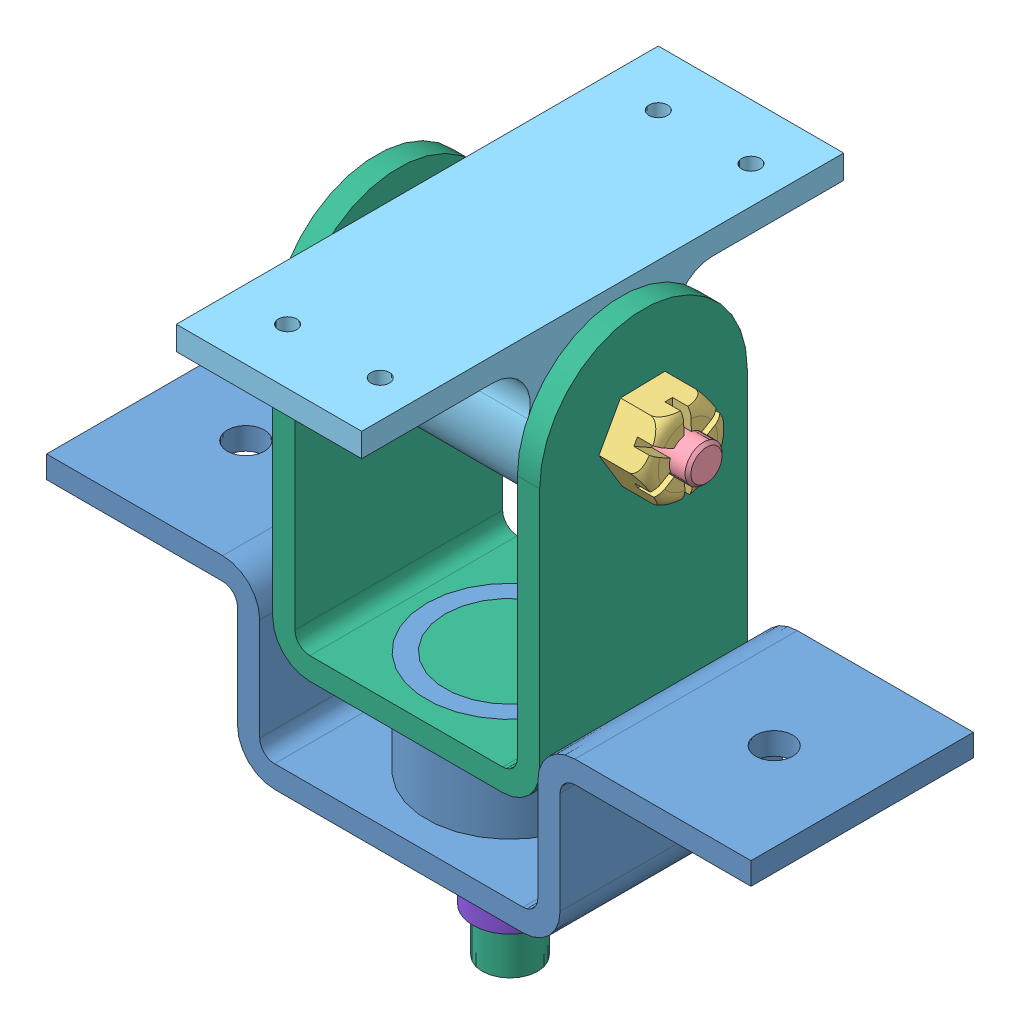
SolidWorks assembly Assem1, configuration Default. Lengths in mm.
Overall size (950 845 650).
9 component instances, 8 part files, 19 mates.
Components (placement in the parent):
- Braket-1: Braket [Default] at (414.4742 324.3872 733.1991) x (1 0 0) z (0 -1 0) size (950 300 238)
- Bushing-1: Bushing [Default] at (501.9742 844.3872 733.1991) x (0 0.51814 -0.855296) z (0 -0.855296 -0.51814) size (200 125 200)
- Castle Nut-1: Castle Nut [Default] at (624.4742 844.3872 733.1991) x (0 0.875235 -0.483697) z (0 -0.483697 -0.875235) size (123.23 61.16 107.14)
- Hexagonal Bolt-1: Hexagonal Bolt [Default] at (679.4742 844.3872 733.1991) x (0 -0.652538 0.757756) z (0 -0.757756 -0.652538) size (126.08 492.24 109.99)
- Pivot-1: Pivot [Default] at (414.4742 857.3872 733.1991) x (0 0 -1) z (1 0 0) size (650 238 250)
- U-Support-1: U-Support [Default] at (414.4742 139.3872 733.1991) size (360 845 280)
- Washer-1: Washer [Default] at (414.4742 319.3872 733.1991) size (165 10 165)
- Bushing-2: Bushing [Default] at (326.9742 844.3872 733.1991) x (0 0.946184 -0.32363) z (0 0.32363 0.946184) size (200 125 200)
- Self Locking Nut-2: Self Locking Nut [Default] at (414.4742 281.8872 733.1991) x (1 0 0) z (0 0 -1) size (188.7 115 164.72)
Mates (geometry in assembly coordinates):
- Coincident2: coincident aligned: circle of Braket-1; plane of U-Support-1 through (414.4742 494.3872 506.1991) normal (0 1 0)
- Coincident3: coincident anti-aligned: circle of Braket-1; cylinder of U-Support-1 through (414.4742 464.3872 733.1991) axis (0 -1 0) radius 37.5
- Coincident5: coincident aligned: plane of Hexagonal Bolt-1 through (234.4742 844.3872 733.1991) normal (1 0 0); circle of U-Support-1
- Concentric1: concentric aligned: cylinder of Hexagonal Bolt-1 through (234.4742 844.3872 733.1991) axis (1 0 0) radius 25; cylinder of U-Support-1 through (227.4742 844.3872 733.1991) axis (1 0 0) radius 25
- Concentric2: concentric anti-aligned: cylinder of Castle Nut-1 through (654.4742 844.3872 733.1991) axis (-1 0 0) radius 25; cylinder of Hexagonal Bolt-1 through (234.4742 844.3872 733.1991) axis (1 0 0) radius 25
- Coincident8: coincident anti-aligned: plane of Castle Nut-1 through (594.4742 844.3872 733.1991) normal (-1 0 0); plane of U-Support-1 through (594.4742 984.3872 873.1991) normal (1 0 0)
- Perpendicular1: perpendicular: plane of Castle Nut-1 through (654.4742 896.9402 704.1558) normal (0 0.999825 0.018724); plane of U-Support-1 through (594.4742 984.3872 873.1991) normal (1 0 0)
- Concentric3: concentric aligned: cylinder of Bushing-1 through (564.4742 844.3872 733.1991) axis (1 0 0) radius 75; cylinder of Pivot-1 through (272.4742 844.3872 733.1991) axis (1 0 0) radius 75
- Coincident10: coincident anti-aligned: plane of Bushing-1 through (539.4742 883.2477 669.052) normal (-1 0 0); plane of Pivot-1 through (539.4742 738.5885 739.7281) normal (1 0 0)
- Concentric4: concentric anti-aligned: circle of Bushing-2; circle of Pivot-1
- Coincident11: coincident anti-aligned: plane of Pivot-1 through (289.4742 738.5885 739.7281) normal (-1 0 0); plane of Bushing-2 through (289.4742 915.351 708.9269) normal (1 0 0)
- Concentric5: concentric anti-aligned: cylinder of Hexagonal Bolt-1 through (234.4742 844.3872 733.1991) axis (1 0 0) radius 25; cylinder of Bushing-2 through (264.4742 844.3872 733.1991) axis (-1 0 0) radius 25
- Coincident12: coincident anti-aligned: plane of U-Support-1 through (264.4742 139.3872 506.1991) normal (1 0 0); plane of Bushing-2 through (264.4742 868.0418 725.1084) normal (-1 0 0)
- Coincident13: coincident aligned: circle of Braket-1; plane of Washer-1 through (414.4742 324.3872 733.1991) normal (0 1 0)
- Coincident14: coincident anti-aligned: plane of Braket-1 through (414.4742 324.3872 733.1991) normal (0 -1 0); plane of Washer-1 through (414.4742 324.3872 733.1991) normal (0 1 0)
- Concentric6: concentric aligned: cylinder of U-Support-1 through (414.4742 464.3872 733.1991) axis (0 -1 0) radius 37.5; cylinder of Washer-1 through (414.4742 324.3872 733.1991) axis (0 -1 0) radius 37.5
- Coincident15: coincident anti-aligned: plane of Washer-1 through (414.4742 314.3872 733.1991) normal (0 -1 0); plane of Self Locking Nut-2 through (414.4742 314.3872 733.1991) normal (0 1 0)
- Concentric7: concentric anti-aligned: cylinder of U-Support-1 through (414.4742 464.3872 733.1991) axis (0 -1 0) radius 37.5; cylinder of Self Locking Nut-2 through (414.4742 199.3872 733.1991) axis (0 1 0) radius 37.5
- Parallel3: parallel aligned: plane of Pivot-1 through (414.4742 976.3872 733.1991) normal (0 1 0); plane of U-Support-1 through (414.4742 494.3872 506.1991) normal (0 1 0)
